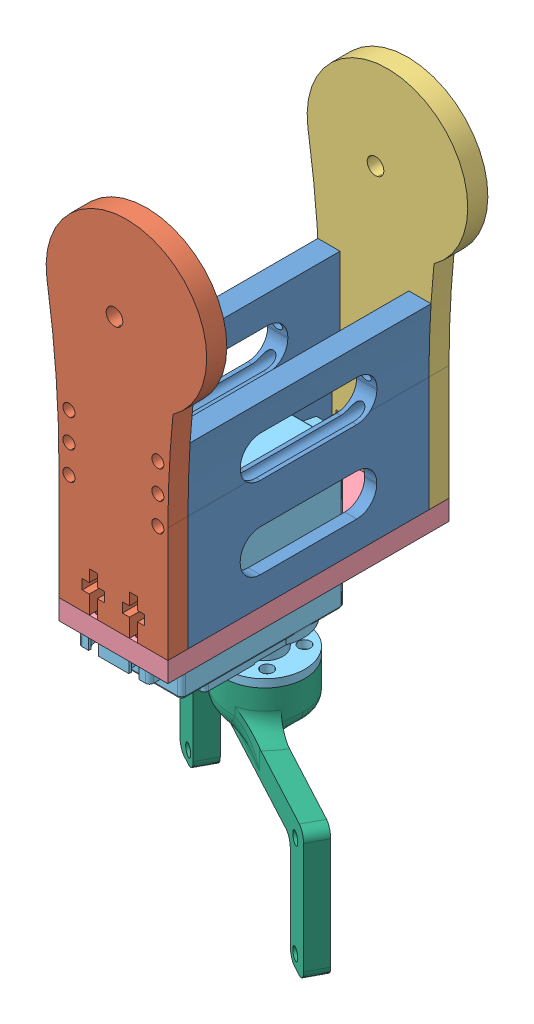
SolidWorks assembly JuntaSecundaria], configuration Valor predeterminado. Lengths in mm.
Overall size (75.57 157.19 70).
7 component instances, 6 part files, 17 mates.
Components (placement in the parent):
- PSL esquerda-1: PSL esquerda [Valor predeterminado] at (-10.1158 -52.8118 30) size (5.52 44.7 60)
- PS DIREITA-2: PS DIREITA [Valor predeterminado] at (-10.1158 -52.8118 90) size (40 90 5)
- PS ESQUERDA-1: PS ESQUERDA [Valor predeterminado] at (-10.1158 -52.8118 25) size (40 90 5)
- PSL esquerda-2: PSL esquerda [Valor predeterminado] at (-10.1158 -52.8118 90) x (-1 0 0) z (0 0 -1) size (5.52 44.7 60)
- SuporteServoGarra-1: SuporteServoGarra [Valor predeterminado] at (-16.2216 -30.0963 51.7505) x (0 0 1) z (0 1 0) size (70 27.14 5)
- Servo-MG-995-1: Servo-MG-995 [Valor predeterminado] at (-14.1523 -20.4258 -5.5896) x (-1 0 0) z (0 0 1) size (20 46.48 67)
- SuporteGarra-1: SuporteGarra [Valor predeterminado] at (-4.9505 -77.565 60.0715) x (-0.881873 0 -0.471488) z (-0.471488 0 0.881873) size (75 42.69 20)
Mates (geometry in assembly coordinates):
- Coincidente4: coincident anti-aligned: plane of PSL esquerda-1 through (-10.1158 -52.8118 30) normal (0 0 -1); plane of PS ESQUERDA-1 through (-10.1158 -52.8118 30) normal (0 0 1)
- Coincidente6: coincident anti-aligned: plane of PS ESQUERDA-1 through (-10.1158 -52.8118 30) normal (0 0 1); plane of PSL esquerda-2 through (-10.1158 -52.8118 30) normal (0 0 -1)
- Coincidente7: coincident anti-aligned: line of PS ESQUERDA-1 through (-23.6849 3.5271 30) axis (0 0 -1); line of PSL esquerda-2 through (-23.6849 3.5271 30) axis (0 0 1)
- Coincidente9: coincident aligned: plane of PS ESQUERDA-1 through (-23.6849 -52.8118 30) normal (-1 0 0); plane of PSL esquerda-2 through (-23.6849 -52.8118 30) normal (-1 0 0)
- Coincidente10: coincident anti-aligned: plane of PS DIREITA-2 through (-10.1158 -52.8118 90) normal (0 0 -1); plane of PSL esquerda-2 through (-10.1158 -52.8118 90) normal (0 0 1)
- Concêntrico1: concentric aligned: circle of PS DIREITA-2; circle of PS ESQUERDA-1
- Coincidente13: coincident aligned: plane of PS DIREITA-2 through (-23.6849 -52.8118 95) normal (-1 0 0); plane of PSL esquerda-2 through (-23.6849 -52.8118 30) normal (-1 0 0)
- Coincidente14: coincident aligned: plane of PSL esquerda-1 through (3.4534 -52.8118 90) normal (1 0 0); plane of PS DIREITA-2 through (3.4534 -52.8118 95) normal (1 0 0)
- Coincidente15: coincident anti-aligned: plane of PS ESQUERDA-1 through (3.4534 -25.0963 25) normal (0 -1 0); plane of SuporteServoGarra-1 through (-16.2216 -25.0963 51.7505) normal (0 1 0)
- Coincidente16: coincident aligned: plane of PS DIREITA-2 through (-10.1158 -52.8118 95) normal (0 0 1); plane of SuporteServoGarra-1 through (3.4551 -25.0963 95) normal (0 0 1)
- Coincidente17: coincident aligned: plane of PSL esquerda-2 through (-23.6849 -52.8118 30) normal (-1 0 0); plane of SuporteServoGarra-1 through (-23.6849 -25.0963 25) normal (-1 0 0)
- Coincidente18: coincident anti-aligned: plane of SuporteServoGarra-1 through (-16.2216 -30.0963 51.7505) normal (0 -1 0); plane of Servo-MG-995-1 through (-10.1149 -30.0963 67.6104) normal (0 1 0)
- Concêntrico4: concentric aligned: circle of SuporteServoGarra-1; circle of Servo-MG-995-1
- Concêntrico5: concentric anti-aligned: circle of SuporteServoGarra-1; circle of Servo-MG-995-1
- Coincidente20: coincident anti-aligned: plane of Servo-MG-995-1 through (-10.1149 -49.5963 57.3104) normal (0 -1 0); plane of SuporteGarra-1 through (-10.1149 -49.5963 57.3104) normal (0 1 0)
- Coincidente21: coincident aligned: circle of Servo-MG-995-1; circle of SuporteGarra-1
- Coincidente22: coincident: plane of PSL esquerda-1 through (3.4534 -25.0963 30) normal (0 -1 0); line of SuporteServoGarra-1 through (-23.6849 -25.0963 95) axis (1 0 0)
